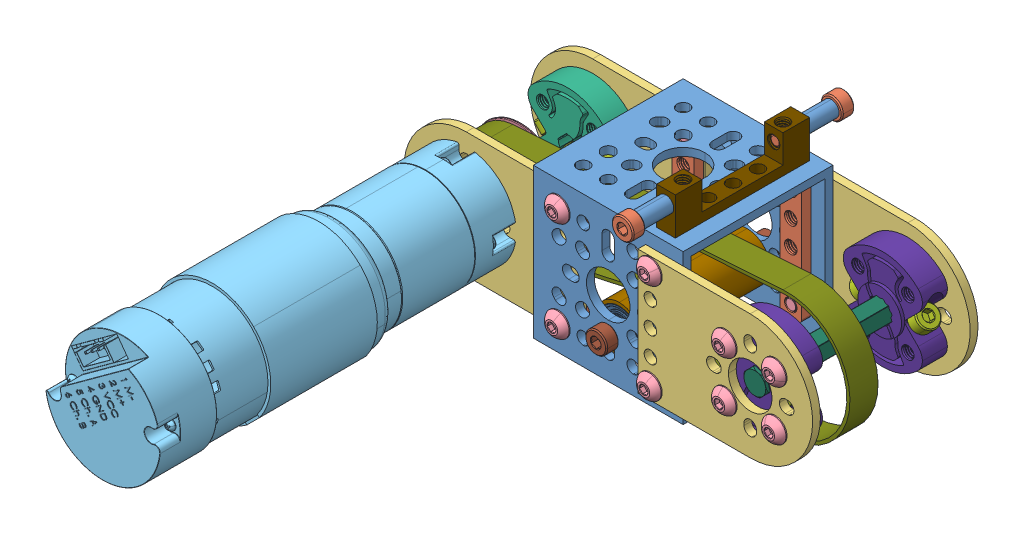
SolidWorks assembly Link3_Assembly, configuration Default. Lengths in mm.
Overall size (149.29 60 173.71).
72 component instances, 20 part files, 80 mates.
Components (placement in the parent):
- 1120-0001-0048-1: 1120-0001-0048 [Default] at (24 21.5 0) x (0 0 -1) z (0 1 0) size (48 48 48)
- 2803-0039-0007-1: 2803-0039-0007 [Default] at (-16 0 16) x (0 -1 0) z (-1 0 0) size (39 3.01 7)
- 1108-0001-0001-1: 1108-0001-0001 [Default] at (-48 0 20.25) x (0 -1 0) z (1 0 0) size (40 2.5 56)
- 1108-0001-0001-2: 1108-0001-0001 [Default] at (48 0 25.25) x (0 -1 0) z (-1 0 0) size (40 2.5 56)
- 2803-0039-0007-2: 2803-0039-0007 [Default] at (16 0 18.5) x (0 -1 0) z (-1 0 0) size (39 3.01 7)
- 1108-0001-0001-3: 1108-0001-0001 [Default] at (48 0 -25.25) x (0 1 0) z (-1 0 0) size (40 2.5 56)
- 2803-0039-0007-3: 2803-0039-0007 [Default] at (16 0 -21.499) x (0 -1 0) z (-1 0 0) size (39 3.01 7)
- 2803-0039-0007-4: 2803-0039-0007 [Default] at (-16 0 -18.999) x (0 -1 0) z (-1 0 0) size (39 3.01 7)
- 1108-0001-0001-4: 1108-0001-0001 [Default] at (-48 0 -20.25) x (0 1 0) z (1 0 0) size (40 2.5 56)
- 2802-0004-0008-2: 2802-0004-0008 [Default] at (16 16 28.7) x (-0.61003 0.792378 0) z (0 0 1) size (7.6 7.6 10.21)
- 2802-0004-0008-3: 2802-0004-0008 [Default] at (16 -16 28.7) x (0.956811 -0.290709 0) z (0 0 1) size (7.6 7.6 10.21)
- 2802-0004-0008-5: 2802-0004-0008 [Default] at (-16 16 26.2) x (0.956811 -0.290709 0) z (0 0 1) size (7.6 7.6 10.21)
- 2802-0004-0008-6: 2802-0004-0008 [Default] at (-16 -16 26.2) x (0.956811 -0.290709 0) z (0 0 1) size (7.6 7.6 10.21)
- 2802-0004-0008-7: 2802-0004-0008 [Default] at (-16 -16 -26.2) x (0.956811 -0.290709 0) z (0 0 -1) size (7.6 7.6 10.21)
- 2802-0004-0008-8: 2802-0004-0008 [Default] at (-16 16 -26.2) x (0.956811 -0.290709 0) z (0 0 -1) size (7.6 7.6 10.21)
- 2802-0004-0008-9: 2802-0004-0008 [Default] at (16 16 -28.7) x (0.61003 -0.792378 0) z (0 0 -1) size (7.6 7.6 10.21)
- 2802-0004-0008-10: 2802-0004-0008 [Default] at (16 -16 -28.7) x (0.956811 -0.290709 0) z (0 0 -1) size (7.6 7.6 10.21)
- 5202-0002-0019 part-1: 5202-0002-0019 part [Default] at (-48 0 21.5) x (-1 0 0) z (0 0 -1) size (37.5 37.5 140.7)
- 2802-0004-0008-11: 2802-0004-0008 [Default] at (-40 -8 16.8) x (0.956811 -0.290709 0) z (0 0 -1) size (7.6 7.6 10.21)
- 2802-0004-0008-12: 2802-0004-0008 [Default] at (-56 8 16.8) x (0.956811 -0.290709 0) z (0 0 -1) size (7.6 7.6 10.21)
- 2802-0004-0008-13: 2802-0004-0008 [Default] at (-56 -8 16.8) x (0.956811 -0.290709 0) z (0 0 -1) size (7.6 7.6 10.21)
- 2802-0004-0008-14: 2802-0004-0008 [Default] at (-40 8 16.8) x (0.997226 -0.074427 0) z (0 0 -1) size (7.6 7.6 10.21)
- 1309-0016-1006 assembly-1: 1309-0016-1006 assembly [Default] at (-66.2019 -0.5776 -6.2264) x (-1 0 0) z (0 0 -1) size (28.36 32 10.95)
  - 1309-0016-1006 assembly.STEP-1: 1309-0016-1006 assembly.STEP [Default] at origin size (28.36 32 10.95)
    - 1309-0016-1006.STEP-1: 1309-0016-1006.STEP [Default] at (-18.2019 0.5776 8.7736) size (25.38 32 10)
    - 2800-0004-0014_90128A207.STEP-1: 2800-0004-0014_90128A207.STEP [Default] at (-16.149 11.6963 8.7736) x (0.5 -0.5 -0.707107) z (0.707107 0.707107 0) size (7 7 18.01)
    - 2800-0004-0014_90128A207.STEP-2: 2800-0004-0014_90128A207.STEP [Default] at (-20.2547 -10.5411 8.7736) x (-0.5 0.5 -0.707107) z (-0.707107 -0.707107 0) size (7 7 18.01)
- 2802-0004-0008-15: 2802-0004-0008 [Default] at (-40 -8 -23.7) x (0.956811 -0.290709 0) z (0 0 -1) size (7.6 7.6 10.21)
- 2802-0004-0008-16: 2802-0004-0008 [Default] at (-56 8 -23.7) x (0.956811 -0.290709 0) z (0 0 -1) size (7.6 7.6 10.21)
- 2802-0004-0008-17: 2802-0004-0008 [Default] at (-56 -8 -23.7) x (0.956811 -0.290709 0) z (0 0 -1) size (7.6 7.6 10.21)
- 2802-0004-0008-18: 2802-0004-0008 [Default] at (-40 8 -23.7) x (0.956811 -0.290709 0) z (0 0 -1) size (7.6 7.6 10.21)
- 1501-0006-0430-2: 1501-0006-0430 [Default] at (0 -11.3137 0) x (0.701906 -0.71227 0) z (0.71227 0.701906 0) size (5.95 43.01 5.95)
- 1607-0041-0615 assembly-1: 1607-0041-0615 assembly [Default] at (22.1413 -6.1132 -9.5426) x (1 0 0) z (0 -1 0) size (17.04 41 17.04)
  - 1607-0041-0615 assembly.STEP-1: 1607-0041-0615 assembly.STEP [Default] at origin size (17.04 41 17.04)
    - 1607-0041-0615.STEP-1: 1607-0041-0615.STEP [Default] at (-22.1413 9.5426 5.2006) size (15 41 15)
    - 1600-0513-0006.STEP-1: 1600-0513-0006.STEP [Default] at (-22.1413 25.0426 5.2006) x (0.920811 0 -0.39001) z (0.39001 0 0.920811) size (13 5 13)
    - 1600-0513-0006.STEP-2: 1600-0513-0006.STEP [Default] at (-22.1413 -10.9574 5.2006) x (0.948511 0 0.316745) z (-0.316745 0 0.948511) size (13 5 13)
- 2800-0004-0010-1: 2800-0004-0010 [Default] at (0 -11.3137 -14) size (7 7 14.01)
- 2800-0004-0010-2: 2800-0004-0010 [Default] at (0 -11.3137 14) x (1 0 0) z (0 0 -1) size (7 7 14.01)
- 3414-1006-0016 assembly-1: 3414-1006-0016 assembly [Default] at (-26.1413 -11.7861 65.4679) x (0 0 1) z (-0.994154 0.10797 0) size (12.01 27.98 27.98)
  - 3414-1006-0016 assembly.STEP-1: 3414-1006-0016 assembly.STEP [Default] at origin size (12.01 27.98 27.98)
    - 3414-1006-0016 body.STEP-1: 3414-1006-0016 body.STEP [Default] at (-62.7232 -4.1348 4.7756) size (12 23.97 23.97)
    - 3414-4008-0016 ring.STEP-1: 3414-4008-0016 ring.STEP [Default] at (-50.8429 9.3571 23.0035) x (0 -1 0) z (0 0 1) size (27.98 1.38 27.98)
    - 3414-4008-0016 ring.STEP-2: 3414-4008-0016 ring.STEP [Default] at (-60.0929 9.3571 23.0035) x (0 -1 0) z (0 0 -1) size (27.98 1.38 27.98)
    - 2806-0005-0006_91390A118.STEP-1: 2806-0005-0006_91390A118.STEP [Default] at (-55.4679 9.3571 17.1119) x (-0.607877 0.794031 0) z (0 0 -1) size (5.01 5.01 6.01)
- 2802-0004-0008-19: 2802-0004-0008 [Default] at (40 8 28.7) x (-0.954358 0.298666 0) z (0 0 1) size (7.6 7.6 10.21)
- 2802-0004-0008-20: 2802-0004-0008 [Default] at (56 8 28.7) x (-0.186029 -0.982544 0) z (0 0 1) size (7.6 7.6 10.21)
- 2802-0004-0008-21: 2802-0004-0008 [Default] at (40 -8 28.7) x (-0.996233 -0.086721 0) z (0 0 1) size (7.6 7.6 10.21)
- 2802-0004-0008-22: 2802-0004-0008 [Default] at (56 -8 28.7) x (-0.815041 -0.579404 0) z (0 0 1) size (7.6 7.6 10.21)
- 2802-0004-0008-23: 2802-0004-0008 [Default] at (40 -8 -28.7) x (-0.996233 -0.086721 0) z (0 0 -1) size (7.6 7.6 10.21)
- 2802-0004-0008-24: 2802-0004-0008 [Default] at (40 8 -28.7) x (-0.954358 0.298666 0) z (0 0 -1) size (7.6 7.6 10.21)
- 2802-0004-0008-25: 2802-0004-0008 [Default] at (56 8 -28.7) x (-0.186029 -0.982544 0) z (0 0 -1) size (7.6 7.6 10.21)
- 2802-0004-0008-26: 2802-0004-0008 [Default] at (56 -8 -28.7) x (-0.815041 -0.579404 0) z (0 0 -1) size (7.6 7.6 10.21)
- 2102-0008-0050-1: 2102-0008-0050 [Default] at (48 0 0) x (0.965926 -0.258819 0) z (-0.258819 -0.965926 0) size (8 50.01 8.01)
- A 6R25M059090-1: A 6R25M059090 [Default] at (-48 0 10.125) x (-1 0 0) z (0 0 -1) size (129.8 40.2 9)
- 1309-0016-4008 assembly-3: 1309-0016-4008 assembly [Default] at (44.0746 -17.6745 9.615) x (-1 0 0) z (0 0 -1) size (28.36 32 9.95)
  - 1309-0016-4008 assembly.STEP-1: 1309-0016-4008 assembly.STEP [Default] at origin size (28.36 32 9.95)
    - 1309-0016-4008.STEP-1: 1309-0016-4008.STEP [Default] at (-3.9254 17.6745 -10.385) size (25.38 32 9.01)
    - 2800-0004-0014_90128A207.STEP-1: 2800-0004-0014_90128A207.STEP [Default] at (-5.9783 6.5558 -10.385) x (0.5 -0.5 0.707107) z (-0.707107 -0.707107 0) size (7 7 18.01)
    - 2800-0004-0014_90128A207.STEP-2: 2800-0004-0014_90128A207.STEP [Default] at (-1.8726 28.7932 -10.385) x (-0.5 0.5 0.707107) z (0.707107 0.707107 0) size (7 7 18.01)
- 1309-0016-4008 assembly-4: 1309-0016-4008 assembly [Default] at (51.9254 -17.6745 -9.615) size (28.36 32 9.95)
  - 1309-0016-4008 assembly.STEP-1: 1309-0016-4008 assembly.STEP [Default] at origin size (28.36 32 9.95)
    - 1309-0016-4008.STEP-1: 1309-0016-4008.STEP [Default] at (-3.9254 17.6745 -10.385) size (25.38 32 9.01)
    - 2800-0004-0014_90128A207.STEP-1: 2800-0004-0014_90128A207.STEP [Default] at (-5.9783 6.5558 -10.385) x (0.5 -0.5 0.707107) z (-0.707107 -0.707107 0) size (7 7 18.01)
    - 2800-0004-0014_90128A207.STEP-2: 2800-0004-0014_90128A207.STEP [Default] at (-1.8726 28.7932 -10.385) x (-0.5 0.5 0.707107) z (0.707107 0.707107 0) size (7 7 18.01)
- 1205-0001-0003-1: 1205-0001-0003 [Default] at (16 30 0) x (0 0 1) z (0 -1 0) size (43.01 6 12.01)
- 2802-0004-0008-27: 2802-0004-0008 [Default] at (16 19.3 -16) x (0.61003 0 0.792378) z (0 -1 0) size (7.6 7.6 10.21)
- 2802-0004-0008-29: 2802-0004-0008 [Default] at (16 19.3 16) x (-0.61003 0 0.792378) z (0 -1 0) size (7.6 7.6 10.21)
- 1502-0005-0100-1: 1502-0005-0100 [Default] at (16 32 -31.5) x (1 0 0) z (0 -1 0) size (5 10 5)
- 2800-0004-0018-1: 2800-0004-0018 [Default] at (16 32 -13.5) size (7 7 22.01)
- 1502-0005-0100-2: 1502-0005-0100 [Default] at (16 32 31.5) x (-1 0 0) z (0 -1 0) size (5 10 5)
- 2800-0004-0018-2: 2800-0004-0018 [Default] at (16 32 13.5) x (1 0 0) z (0 0 -1) size (7 7 22.01)
Mates (geometry in assembly coordinates):
- Symmetric1: symmetric aligned: plane of 1120-0001-0048-1 through (-24 24 -24) normal (0 1 0); plane of 1120-0001-0048-1 through (-24 -24 -21.5) normal (0 -1 0)
- Coincident1: coincident anti-aligned: plane of 1120-0001-0048-1 through (24 21.5 0) normal (0 0 -1)
- Symmetric2: symmetric aligned: plane of 1120-0001-0048-1 through (24 21.5 0) normal (1 0 0); plane of 1120-0001-0048-1 through (-24 21.5 0) normal (-1 0 0)
- Coincident2: coincident anti-aligned: plane of 1120-0001-0048-1 through (-24 21.5 21.5) normal (0 0 -1); plane of 1108-0001-0001-1 through (-48 0 21.5) normal (0 0 1)
- Concentric1: concentric anti-aligned: cylinder of 1120-0001-0048-1 through (-16 16 14) axis (0 0 1) radius 2; cylinder of 1108-0001-0001-1 through (-16 16 21.5) axis (0 0 -1) radius 2
- Concentric2: concentric anti-aligned: cylinder of 1120-0001-0048-1 through (-16 -16 14) axis (0 0 1) radius 2; cylinder of 1108-0001-0001-1 through (-16 -16 21.5) axis (0 0 -1) radius 2
- Coincident3: coincident anti-aligned: plane of 1120-0001-0048-1 through (-24 -24 24) normal (0 0 1); plane of 1108-0001-0001-2 through (48 0 24) normal (0 0 -1)
- Concentric3: concentric aligned: cylinder of 1120-0001-0048-1 through (16 16 14) axis (0 0 1) radius 2; cylinder of 1108-0001-0001-2 through (16 16 24) axis (0 0 1) radius 2
- Concentric4: concentric aligned: cylinder of 1120-0001-0048-1 through (16 -16 14) axis (0 0 1) radius 2; cylinder of 1108-0001-0001-2 through (16 -16 24) axis (0 0 1) radius 2
- Coincident4: coincident anti-aligned: plane of 2803-0039-0007-1 through (-16 0 19) normal (0 0 1); plane of 1108-0001-0001-1 through (-48 0 19) normal (0 0 -1)
- Coincident5: coincident anti-aligned: circle of 2803-0039-0007-1; cylinder of 1108-0001-0001-1 through (-16 16 21.5) axis (0 0 -1) radius 2
- Concentric5: concentric anti-aligned: circle of 2803-0039-0007-1; cylinder of 1108-0001-0001-1 through (-16 -16 21.5) axis (0 0 -1) radius 2
- Coincident7: coincident anti-aligned: plane of 1120-0001-0048-1 through (-24 21.5 21.5) normal (0 0 -1); plane of 2803-0039-0007-2 through (16 0 21.5) normal (0 0 1)
- Coincident8: coincident aligned: cylinder of 1120-0001-0048-1 through (16 16 14) axis (0 0 1) radius 2; circle of 2803-0039-0007-2
- Coincident9: coincident aligned: cylinder of 1120-0001-0048-1 through (16 -16 14) axis (0 0 1) radius 2; circle of 2803-0039-0007-2
- Coincident12: coincident aligned: plane of 2802-0004-0008-2 through (19.011 18.3181 26.5) normal (0 0 -1); plane of 2802-0004-0008-3 through (14.8953 -19.6359 26.5) normal (0 0 -1)
- Coincident13: coincident anti-aligned: plane of 1108-0001-0001-2 through (48 0 26.5) normal (0 0 1); plane of 2802-0004-0008-2 through (19.011 18.3181 26.5) normal (0 0 -1)
- Concentric6: concentric aligned: cylinder of 1108-0001-0001-2 through (16 16 24) axis (0 0 1) radius 2; cylinder of 2802-0004-0008-2 through (16 16 28.7) axis (0 0 1) radius 3.8
- Concentric7: concentric aligned: cylinder of 1108-0001-0001-2 through (16 -16 24) axis (0 0 1) radius 2; cylinder of 2802-0004-0008-3 through (16 -16 28.7) axis (0 0 1) radius 3.8
- Coincident14: coincident aligned: plane of 2802-0004-0008-5 through (-16.5814 14.0864 26.2) normal (0 0 1); plane of 2802-0004-0008-6 through (-16.5814 -17.9136 26.2) normal (0 0 1)
- Coincident15: coincident anti-aligned: plane of 1120-0001-0048-1 through (-24 -24 24) normal (0 0 1); plane of 2802-0004-0008-5 through (-17.1047 12.3641 24) normal (0 0 -1)
- Concentric8: concentric aligned: cylinder of 1120-0001-0048-1 through (-16 -16 14) axis (0 0 1) radius 2; cylinder of 2802-0004-0008-6 through (-16 -16 26.2) axis (0 0 1) radius 3.8
- Concentric9: concentric aligned: cylinder of 1120-0001-0048-1 through (-16 16 14) axis (0 0 1) radius 2; cylinder of 2802-0004-0008-5 through (-16 16 26.2) axis (0 0 1) radius 3.8
- Concentric10: concentric anti-aligned: cylinder of 1108-0001-0001-1 through (-48 0 21.5) axis (0 0 -1) radius 7; cylinder of 5202-0002-0019 part-1 through (-48 0 24.55) axis (0 0 1) radius 16
- Coincident16: coincident anti-aligned: cylinder of 1108-0001-0001-1 through (-56 8 21.5) axis (0 0 -1) radius 2; circle of 5202-0002-0019 part-1
- Coincident17: coincident anti-aligned: plane of 1108-0001-0001-1 through (-48 0 21.5) normal (0 0 1); plane of 5202-0002-0019 part-1 through (-48 0 21.5) normal (0 0 -1)
- Coincident18: coincident aligned: plane of 2802-0004-0008-13 through (-55.4186 -6.0864 16.8) normal (0 0 -1); plane of 2802-0004-0008-14 through (-39.8511 9.9945 16.8) normal (0 0 -1)
- Coincident19: coincident aligned: plane of 2802-0004-0008-12 through (-55.4186 9.9136 16.8) normal (0 0 -1); plane of 2802-0004-0008-13 through (-55.4186 -6.0864 16.8) normal (0 0 -1)
- Coincident20: coincident aligned: plane of 2802-0004-0008-11 through (-39.4186 -6.0864 16.8) normal (0 0 -1); plane of 2802-0004-0008-12 through (-55.4186 9.9136 16.8) normal (0 0 -1)
- Concentric11: concentric aligned: cylinder of 1108-0001-0001-1 through (-40 -8 21.5) axis (0 0 -1) radius 2; cylinder of 2802-0004-0008-11 through (-40 -8 16.8) axis (0 0 -1) radius 3.8
- Concentric12: concentric aligned: cylinder of 1108-0001-0001-1 through (-56 8 21.5) axis (0 0 -1) radius 2; circle of 2802-0004-0008-12
- Concentric13: concentric aligned: cylinder of 1108-0001-0001-1 through (-56 -8 21.5) axis (0 0 -1) radius 2; cylinder of 2802-0004-0008-13 through (-56 -8 16.8) axis (0 0 -1) radius 3.8
- Concentric14: concentric aligned: cylinder of 1108-0001-0001-1 through (-40 8 21.5) axis (0 0 -1) radius 2; cylinder of 2802-0004-0008-14 through (-40 8 16.8) axis (0 0 -1) radius 3.8
- Coincident21: coincident anti-aligned: plane of 1108-0001-0001-1 through (-48 0 19) normal (0 0 -1); plane of 2802-0004-0008-14 through (-39.7172 11.7895 19) normal (0 0 1)
- Concentric15: concentric aligned: cylinder of 1108-0001-0001-4 through (-48 0 -21.5) axis (0 0 1) radius 7; cylinder of 1309-0016-1006 assembly-1/1309-0016-1006 assembly.STEP-1/1309-0016-1006.STEP-1 through (-48 0 -20) axis (0 0 1) radius 7
- Coincident22: coincident anti-aligned: plane of 1108-0001-0001-4 through (-48 0 -19) normal (0 0 1); plane of 1309-0016-1006 assembly-1/1309-0016-1006 assembly.STEP-1/1309-0016-1006.STEP-1 through (-48 0 -19) normal (0 0 -1)
- Coincident23: coincident aligned: cylinder of 1108-0001-0001-4 through (-56 8 -21.5) axis (0 0 1) radius 2; circle of 1309-0016-1006 assembly-1/1309-0016-1006 assembly.STEP-1/1309-0016-1006.STEP-1
- Coincident24: coincident aligned: plane of 2802-0004-0008-16 through (-55.4186 9.9136 -23.7) normal (0 0 -1); plane of 2802-0004-0008-17 through (-55.4186 -6.0864 -23.7) normal (0 0 -1)
- Coincident25: coincident aligned: plane of 2802-0004-0008-15 through (-39.4186 -6.0864 -23.7) normal (0 0 -1); plane of 2802-0004-0008-17 through (-55.4186 -6.0864 -23.7) normal (0 0 -1)
- Coincident26: coincident aligned: plane of 2802-0004-0008-17 through (-55.4186 -6.0864 -23.7) normal (0 0 -1); plane of 2802-0004-0008-18 through (-39.4186 9.9136 -23.7) normal (0 0 -1)
- Coincident27: coincident anti-aligned: plane of 1108-0001-0001-4 through (-48 0 -21.5) normal (0 0 -1); plane of 2802-0004-0008-16 through (-54.8953 11.6359 -21.5) normal (0 0 1)
- Concentric16: concentric anti-aligned: cylinder of 1108-0001-0001-4 through (-56 8 -21.5) axis (0 0 1) radius 2; circle of 2802-0004-0008-16
- Concentric17: concentric anti-aligned: cylinder of 1108-0001-0001-4 through (-40 8 -21.5) axis (0 0 1) radius 2; circle of 2802-0004-0008-18
- Concentric18: concentric anti-aligned: circle of 1108-0001-0001-4; circle of 2802-0004-0008-17
- Concentric19: concentric anti-aligned: cylinder of 1108-0001-0001-4 through (-40 -8 -21.5) axis (0 0 1) radius 2; cylinder of 2802-0004-0008-15 through (-40 -8 -23.7) axis (0 0 -1) radius 3.8
- Concentric22: concentric anti-aligned: cylinder of 1120-0001-0048-1 through (0 -11.3137 -21) axis (0 0 -1) radius 2; cylinder of 1501-0006-0430-2 through (0 -11.3137 -21.5) axis (0 0 1) radius 2.975
- Coincident28: coincident anti-aligned: plane of 1120-0001-0048-1 through (-24 21.5 -21.5) normal (0 0 1); plane of 1501-0006-0430-2 through (0 -11.3137 -21.5) normal (0 0 -1)
- Concentric23: concentric anti-aligned: cylinder of 1501-0006-0430-2 through (0 -11.3137 -21.5) axis (0 0 1) radius 2.975; cylinder of 1607-0041-0615 assembly-1/1607-0041-0615 assembly.STEP-1/1607-0041-0615.STEP-1 through (0 -11.3137 20.5) axis (0 0 -1) radius 7.5
- Symmetric3: symmetric aligned: plane of 1607-0041-0615 assembly-1/1607-0041-0615 assembly.STEP-1/1607-0041-0615.STEP-1 through (0 -11.3137 20.5) normal (0 0 1); plane of 1607-0041-0615 assembly-1/1607-0041-0615 assembly.STEP-1/1607-0041-0615.STEP-1 through (0 -11.3137 -20.5) normal (0 0 -1)
- Coincident30: coincident anti-aligned: plane of 1120-0001-0048-1 through (-24 -24 -24) normal (0 0 -1); plane of 2800-0004-0010-1 through (0 -11.3137 -24) normal (0 0 1)
- Concentric25: concentric anti-aligned: cylinder of 1120-0001-0048-1 through (0 -11.3137 -21) axis (0 0 -1) radius 2; cylinder of 2800-0004-0010-1 through (0 -11.3137 -28) axis (0 0 1) radius 3.5
- Distance1: distance = 3 mm anti-aligned: plane of 3414-1006-0016 assembly-1/3414-1006-0016 assembly.STEP-1/3414-1006-0016 body.STEP-1 through (-53.2176 10.5111 16) normal (0 0 1); plane of 1108-0001-0001-1 through (-48 0 19) normal (0 0 -1)
- Concentric27: concentric aligned: cylinder of 5202-0002-0019 part-1 through (-48 0 -2.5) axis (0 0 1) radius 3; cylinder of 3414-1006-0016 assembly-1/3414-1006-0016 assembly.STEP-1/3414-1006-0016 body.STEP-1 through (-48 0 -6.6301) axis (0 0 1) radius 3
- Parallel1: parallel anti-aligned: plane of 5202-0002-0019 part-1 through (-45.7513 -1.9857 19) normal (0.994154 -0.10797 0); plane of 3414-1006-0016 assembly-1/3414-1006-0016 assembly.STEP-1/3414-1006-0016 body.STEP-1 through (-46.9912 -13.6808 -6.6301) normal (-0.994154 0.10797 0)
- Coincident33: coincident aligned: plane of 2802-0004-0008-21 through (39.8266 -6.0075 28.7) normal (0 0 1); plane of 2802-0004-0008-22 through (54.8412 -6.3699 28.7) normal (0 0 1)
- Coincident34: coincident aligned: plane of 2802-0004-0008-19 through (40.5973 9.9087 28.7) normal (0 0 1); plane of 2802-0004-0008-21 through (39.8266 -6.0075 28.7) normal (0 0 1)
- Coincident35: coincident aligned: plane of 2802-0004-0008-20 through (54.0349 8.3721 28.7) normal (0 0 1); plane of 2802-0004-0008-21 through (39.8266 -6.0075 28.7) normal (0 0 1)
- Concentric30: concentric aligned: cylinder of 1108-0001-0001-2 through (56 -8 24) axis (0 0 1) radius 2; cylinder of 2802-0004-0008-22 through (56 -8 28.7) axis (0 0 1) radius 3.8
- Coincident36: coincident anti-aligned: plane of 1108-0001-0001-2 through (48 0 26.5) normal (0 0 1); plane of 2802-0004-0008-21 through (39.6705 -4.2143 26.5) normal (0 0 -1)
- Concentric31: concentric aligned: cylinder of 1108-0001-0001-2 through (40 -8 24) axis (0 0 1) radius 2; cylinder of 2802-0004-0008-21 through (40 -8 28.7) axis (0 0 1) radius 3.8
- Concentric32: concentric aligned: cylinder of 1108-0001-0001-2 through (40 8 24) axis (0 0 1) radius 2; circle of 2802-0004-0008-19
- Concentric33: concentric aligned: cylinder of 1108-0001-0001-2 through (56 8 24) axis (0 0 1) radius 2; circle of 2802-0004-0008-20
- Concentric34: concentric anti-aligned: cylinder of 1108-0001-0001-2 through (48 0 24) axis (0 0 1) radius 7; cylinder of 2102-0008-0050-1 through (48 0 25) axis (0 0 -1) radius 4
- Coincident39: coincident aligned: plane of 2102-0008-0050-1 through (48 0 0) normal (0 0 1)
- Concentric35: concentric aligned: cylinder of 5202-0002-0019 part-1 through (-48 0 -2.5) axis (0 0 1) radius 3; cylinder of A 6R25M059090-1 through (-48 0 5.625) axis (0 0 1) radius 13.7
- Coincident40: coincident anti-aligned: plane of 3414-1006-0016 assembly-1/3414-1006-0016 assembly.STEP-1/3414-4008-0016 ring.STEP-1 through (-48 0 14.625) normal (0 0 -1); plane of A 6R25M059090-1 through (-48 0 14.625) normal (0 0 1)
- Concentric36: concentric aligned: cylinder of 1108-0001-0001-2 through (48 0 24) axis (0 0 1) radius 7; cylinder of A 6R25M059090-1 through (48 0 5.625) axis (0 0 1) radius 19.1
- Concentric37: concentric aligned: cylinder of 1108-0001-0001-2 through (48 0 24) axis (0 0 1) radius 7; cylinder of 1309-0016-4008 assembly-3/1309-0016-4008 assembly.STEP-1/1309-0016-4008.STEP-1 through (48 0 15) axis (0 0 1) radius 7
- Coincident41: coincident anti-aligned: plane of 1108-0001-0001-2 through (48 0 24) normal (0 0 -1); plane of 1309-0016-4008 assembly-3/1309-0016-4008 assembly.STEP-1/1309-0016-4008.STEP-1 through (48 0 24) normal (0 0 1)
- Concentric38: concentric anti-aligned: cylinder of 1108-0001-0001-2 through (56 8 24) axis (0 0 1) radius 2; cylinder of 1309-0016-4008 assembly-3/1309-0016-4008 assembly.STEP-1/1309-0016-4008.STEP-1 through (56 8 24) axis (0 0 -1) radius 4.6863
- Coincident42: coincident anti-aligned: plane of 2102-0008-0050-1 through (48.9059 3.3807 25) normal (0.258819 0.965926 0); plane of 1309-0016-4008 assembly-3/1309-0016-4008 assembly.STEP-1/1309-0016-4008.STEP-1 through (48.9059 3.3807 24.1224) normal (-0.258819 -0.965926 0)
- Coincident43: coincident anti-aligned: plane of 1120-0001-0048-1 through (-24 24 -24) normal (0 1 0); plane of 1205-0001-0003-1 through (13 24 0) normal (0 -1 0)
- Coincident44: coincident aligned: cylinder of 1120-0001-0048-1 through (16 14 -16) axis (0 1 0) radius 2; circle of 1205-0001-0003-1
- Coincident45: coincident aligned: cylinder of 1120-0001-0048-1 through (16 14 16) axis (0 1 0) radius 2; circle of 1205-0001-0003-1
- Concentric39: concentric anti-aligned: cylinder of 1120-0001-0048-1 through (16 14 -16) axis (0 1 0) radius 2; cylinder of 2802-0004-0008-27 through (16 19.3 -16) axis (0 -1 0) radius 3.8
- Coincident46: coincident anti-aligned: plane of 1120-0001-0048-1 through (-24 21.5 21.5) normal (0 -1 0); plane of 2802-0004-0008-27 through (19.011 21.5 -18.3181) normal (0 1 0)
- Coincident47: coincident anti-aligned: plane of 1205-0001-0003-1 through (13 30 -21.5) normal (0 0 -1); plane of 1502-0005-0100-1 through (16 32 -21.5) normal (0 0 1)
- Concentric40: concentric aligned: circle of 1205-0001-0003-1; cylinder of 1502-0005-0100-1 through (16 32 -21.5) axis (0 0 -1) radius 2.5
- Concentric41: concentric anti-aligned: cylinder of 1502-0005-0100-1 through (16 32 -21.5) axis (0 0 -1) radius 2.5; cylinder of 2800-0004-0018-1 through (16 32 -35.5) axis (0 0 1) radius 3.5
- Coincident48: coincident anti-aligned: plane of 1502-0005-0100-1 through (16 32 -31.5) normal (0 0 -1); plane of 2800-0004-0018-1 through (16 32 -31.5) normal (0 0 1)
